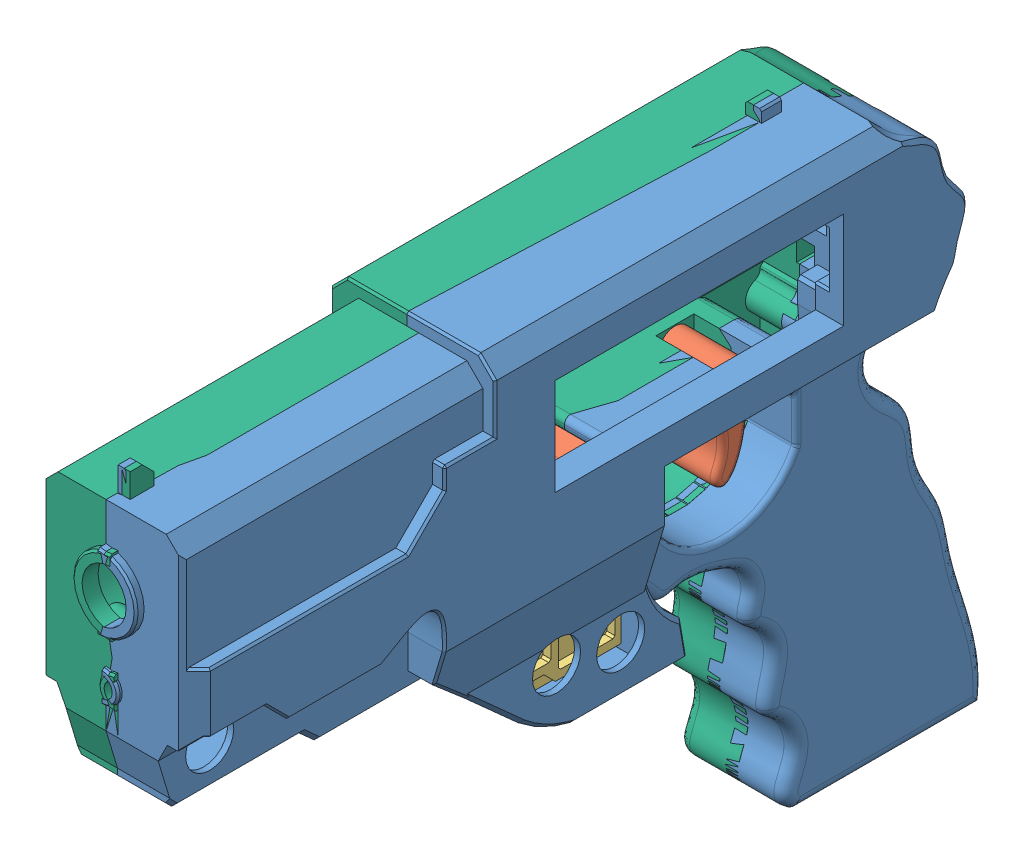
SolidWorks assembly Assemblage_complet, configuration Défaut. Lengths in mm.
Overall size (42.45 144.71 215.3).
7 component instances, 6 part files, 3 mates.
Components (placement in the parent):
- Assemblage_en_coupe-1: Assemblage_en_coupe [Défaut] at (25.1604 -4.9757 215.3016) size (37.15 144.71 215.3)
  - pistolet_cote_circuit-1: pistolet_cote_circuit [Défaut] at (-61.6819 55.6164 215.3016) size (23.45 144.71 215.3)
  - gachette_v3-1: gachette_v3 [Défaut] at (-61.6819 30.8475 67.1148) x (0 -0.031257 0.999511) z (-1 0 0) size (42.56 30.73 27.4)
  - plaque_interrupteur_crosse-1: plaque_interrupteur_crosse [Défaut] at (-55.1819 -2.708 116.1316) x (0 0 1) z (-1 0 0) size (47.34 21.79 4)
  - plaque_interrupteur_canon-1: plaque_interrupteur_canon [Défaut] at (-59.1819 21.0092 190.2537) x (0 0 1) z (-1 0 0) size (32.24 14.2 3.5)
  - coulisseau_v3-1: coulisseau_v3 [Défaut] at (-62.3819 55.6164 150.3016) x (0 -1 0) z (0 0 -1) size (29 16 7)
- pistolet_cote_rien-1: pistolet_cote_rien [Défaut] at (-33.5215 50.6407 430.6031) size (22 144.71 215.3)
Mates (geometry in assembly coordinates):
- Coaxiale1: concentric anti-aligned: cylinder of Assemblage_en_coupe-1/pistolet_cote_circuit-1 through (-23.5215 -63.8185 231.8922) axis (-1 0 0) radius 1.5; cylinder of pistolet_cote_rien-1 through (-56.0031 -63.8185 231.8922) axis (1 0 0) radius 1.8
- Coaxiale2: concentric anti-aligned: cylinder of Assemblage_en_coupe-1/pistolet_cote_circuit-1 through (-23.5215 35.8921 422.4031) axis (-1 0 0) radius 1.5; cylinder of pistolet_cote_rien-1 through (-56.0031 35.8921 422.4031) axis (1 0 0) radius 1.8
- Coïncidente1: coincident anti-aligned: plane of Assemblage_en_coupe-1/pistolet_cote_circuit-1 through (-36.5215 -63.8185 231.8922) normal (-1 0 0); plane of pistolet_cote_rien-1 through (-36.5215 50.6407 430.6031) normal (1 0 0)
